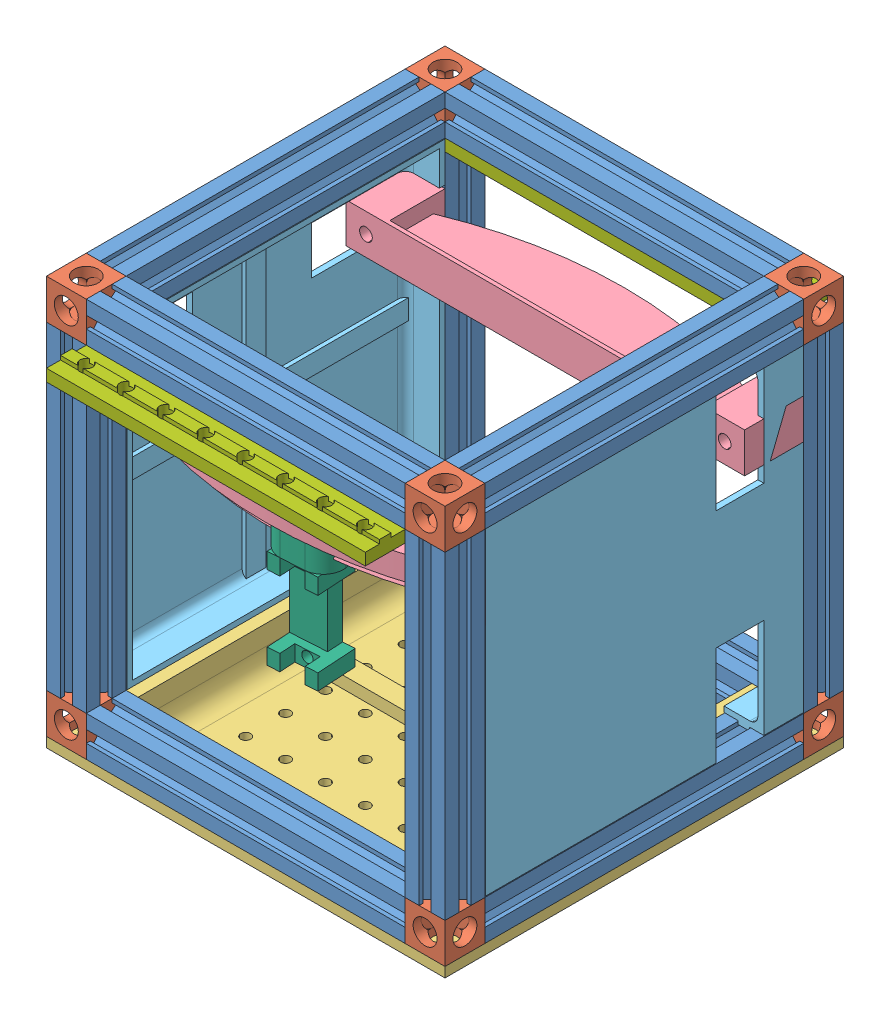
SolidWorks assembly SquareBeaconAssembly, configuration Default. Lengths in mm.
Overall size (100 102.5 120).
28 component instances, 7 part files, 90 mates.
Components (placement in the parent):
- Makerbeam50-1000mm-1: Makerbeam50-1000mm [80mm] at (14.161 43.4255 28.5525) size (10 10 80)
- MakerBeam-cube-1: MakerBeam-cube [Default] at (14.161 48.4255 113.5525) x (1 0 0) z (0 -1 0) size (10 10 10)
- Makerbeam50-1000mm-2: Makerbeam50-1000mm [80mm] at (14.161 128.4255 113.5525) x (1 0 0) z (0 -1 0) size (10 10 80)
- Makerbeam50-1000mm-3: Makerbeam50-1000mm [80mm] at (14.161 128.4255 23.5525) x (1 0 0) z (0 -1 0) size (10 10 80)
- Makerbeam50-1000mm-4: Makerbeam50-1000mm [80mm] at (-70.839 43.4255 113.5525) x (0 0 -1) z (1 0 0) size (10 10 80)
- Makerbeam50-1000mm-5: Makerbeam50-1000mm [80mm] at (-70.839 43.4255 23.5525) x (0 0 -1) z (1 0 0) size (10 10 80)
- MakerBeam-cube-3: MakerBeam-cube [Default] at (9.161 43.4255 23.5525) x (0 -1 0) z (1 0 0) size (10 10 10)
- MakerBeam-cube-4: MakerBeam-cube [Default] at (14.161 128.4255 23.5525) x (1 0 0) z (0 1 0) size (10 10 10)
- Makerbeam50-1000mm-6: Makerbeam50-1000mm [80mm] at (14.161 133.4255 28.5525) size (10 10 80)
- MakerBeam-cube-5: MakerBeam-cube [Default] at (14.161 133.4255 108.5525) size (10 10 10)
- Makerbeam50-1000mm-7: Makerbeam50-1000mm [80mm] at (9.161 133.4255 113.5525) x (0 0 1) z (-1 0 0) size (10 10 80)
- Makerbeam50-1000mm-8: Makerbeam50-1000mm [80mm] at (-70.839 133.4255 23.5525) x (0 0 -1) z (1 0 0) size (10 10 80)
- Makerbeam50-1000mm-9: Makerbeam50-1000mm [80mm] at (-75.839 133.4255 28.5525) size (10 10 80)
- Makerbeam50-1000mm-10: Makerbeam50-1000mm [80mm] at (-75.839 48.4255 113.5525) x (1 0 0) z (0 1 0) size (10 10 80)
- MakerBeam-cube-6: MakerBeam-cube [Default] at (-75.839 133.4255 28.5525) x (-1 0 0) z (0 0 -1) size (10 10 10)
- MakerBeam-cube-7: MakerBeam-cube [Default] at (-70.839 133.4255 113.5525) x (0 0 1) z (-1 0 0) size (10 10 10)
- MakerBeam-cube-8: MakerBeam-cube [Default] at (-70.839 43.4255 113.5525) x (0 -1 0) z (-1 0 0) size (10 10 10)
- Makerbeam50-1000mm-11: Makerbeam50-1000mm [80mm] at (-75.839 43.4255 28.5525) size (10 10 80)
- MakerBeam-cube-9: MakerBeam-cube [Default] at (-70.839 43.4255 23.5525) x (0 0 -1) z (-1 0 0) size (10 10 10)
- Makerbeam50-1000mm-12: Makerbeam50-1000mm [80mm] at (-75.839 128.4255 23.5525) x (1 0 0) z (0 -1 0) size (10 10 80)
- SquareBeaconSupportTop-1: SquareBeaconSupportTop [Default] at (-30.839 35.9255 68.5525) x (1 0 0) z (0 1 0) size (100 100 12.5)
- SquareBeaconVl530xSupport-1: SquareBeaconVl530xSupport [Default] at (-30.839 113.4255 8.5525) x (0 0 1) z (1 0 0) size (19.83 13 100)
- SquareBeaconSide-1: SquareBeaconSide [Default] at (-80.839 88.3255 68.4525) x (0 0 -1) z (1 0 0) size (81.5 81.5 10)
- SquareBeaconSide-2: SquareBeaconSide [Default] at (19.161 88.5255 68.4525) x (0 1 0) z (-1 0 0) size (81.5 81.5 10)
- SquareBeaconVl530xSupport-2: SquareBeaconVl530xSupport [Default] at (-30.839 113.4255 128.5525) x (0 0 -1) z (-1 0 0) size (19.83 13 100)
- TofSupport-1: TofSupport [Default] at (-33.9246 101.4255 -41.4401) x (0.998101 0 -0.061604) z (-0.061604 0 -0.998101) size (15.71 30.8 10.03)
- Bracket_ParallelCorner20x80_slotType2-1: Bracket_ParallelCorner20x80_slotType2 [Default] at (9.161 125.4255 23.5525) x (0 0 1) z (-1 0 0) size (20 4 80)
- Bracket_ParallelCorner20x80_slotType2-2: Bracket_ParallelCorner20x80_slotType2 [Default] at (-70.839 125.4255 113.5525) x (0 0 -1) z (1 0 0) size (20 4 80)
Mates (geometry in assembly coordinates):
- Coincident1: coincident anti-aligned: plane of Makerbeam50-1000mm-1 through (14.161 43.4255 108.5525) normal (0 0 1); plane of MakerBeam-cube-1 through (19.161 38.4255 108.5525) normal (0 0 -1)
- Coincident2: coincident aligned: plane of Makerbeam50-1000mm-1 through (19.161 48.4255 108.5525) normal (1 0 0); plane of MakerBeam-cube-1 through (19.161 38.4255 108.5525) normal (1 0 0)
- Coincident3: coincident aligned: plane of Makerbeam50-1000mm-1 through (9.161 48.4255 108.5525) normal (0 1 0); plane of MakerBeam-cube-1 through (14.161 48.4255 113.5525) normal (0 1 0)
- Coincident4: coincident anti-aligned: plane of MakerBeam-cube-1 through (14.161 48.4255 113.5525) normal (0 1 0); plane of Makerbeam50-1000mm-2 through (14.161 48.4255 113.5525) normal (0 -1 0)
- Coincident5: coincident aligned: plane of MakerBeam-cube-1 through (19.161 38.4255 108.5525) normal (1 0 0); plane of Makerbeam50-1000mm-2 through (19.161 48.4255 112.0525) normal (1 0 0)
- Coincident6: coincident aligned: plane of MakerBeam-cube-1 through (19.161 38.4255 118.5525) normal (0 0 1); plane of Makerbeam50-1000mm-2 through (15.661 48.4255 118.5525) normal (0 0 1)
- Coincident7: coincident: plane of Makerbeam50-1000mm-1 through (19.161 41.9255 108.5525) normal (1 0 0); plane of ? through (19.161 43.4255 23.5525) normal (1 0 0)
- Coincident8: coincident: plane of Makerbeam50-1000mm-1 through (15.661 48.4255 108.5525) normal (0 1 0); plane of ? through (19.161 48.4255 18.5525) normal (0 1 0)
- Coincident9: coincident anti-aligned: plane of Makerbeam50-1000mm-1 through (14.161 43.4255 28.5525) normal (0 0 -1); plane of ? through (19.161 38.4255 28.5525) normal (0 0 1)
- Coincident10: coincident: plane of ? through (19.161 48.4255 18.5525) normal (0 1 0); plane of Makerbeam50-1000mm-3 through (14.161 48.4255 23.4377) normal (0 -1 0)
- Coincident11: coincident: plane of ? through (19.161 48.4255 18.5525) normal (0 1 0); plane of Makerbeam50-1000mm-3 through (14.161 48.4255 23.4377) normal (0 -1 0)
- Coincident12: coincident aligned: plane of ? through (19.161 43.4255 23.5525) normal (1 0 0); plane of Makerbeam50-1000mm-3 through (19.161 48.4255 21.9377) normal (1 0 0)
- Coincident13: coincident anti-aligned: plane of MakerBeam-cube-1 through (9.161 38.4255 108.5525) normal (-1 0 0); plane of Makerbeam50-1000mm-4 through (9.161 43.4255 113.5525) normal (1 0 0)
- Coincident14: coincident aligned: plane of MakerBeam-cube-1 through (19.161 38.4255 118.5525) normal (0 0 1); plane of Makerbeam50-1000mm-4 through (9.161 38.4255 118.5525) normal (0 0 1)
- Coincident15: coincident aligned: plane of MakerBeam-cube-1 through (14.161 38.4255 113.5525) normal (0 -1 0); plane of Makerbeam50-1000mm-4 through (9.161 38.4255 115.0525) normal (0 -1 0)
- Coincident16: coincident anti-aligned: plane of ? through (9.161 43.4255 23.5525) normal (-1 0 0); plane of Makerbeam50-1000mm-5 through (9.161 112.5609 46.3386) normal (1 0 0)
- Coincident17: coincident anti-aligned: plane of Makerbeam50-1000mm-3 through (14.161 48.4255 23.5525) normal (0 -1 0); plane of MakerBeam-cube-3 through (19.161 48.4255 28.5525) normal (0 1 0)
- Coincident18: coincident aligned: plane of Makerbeam50-1000mm-3 through (9.161 48.4255 25.0525) normal (-1 0 0); plane of MakerBeam-cube-3 through (9.161 43.4255 23.5525) normal (-1 0 0)
- Coincident19: coincident anti-aligned: plane of Makerbeam50-1000mm-1 through (14.161 43.4255 28.5525) normal (0 0 -1); plane of MakerBeam-cube-3 through (19.161 38.4255 28.5525) normal (0 0 1)
- Coincident20: coincident anti-aligned: plane of Makerbeam50-1000mm-5 through (9.161 43.4255 23.5525) normal (1 0 0); plane of MakerBeam-cube-3 through (9.161 43.4255 23.5525) normal (-1 0 0)
- Coincident21: coincident aligned: plane of Makerbeam50-1000mm-1 through (9.161 44.9255 108.5525) normal (-1 0 0); plane of MakerBeam-cube-3 through (9.161 43.4255 23.5525) normal (-1 0 0)
- Coincident22: coincident aligned: plane of Makerbeam50-1000mm-5 through (9.161 38.4255 22.0525) normal (0 -1 0); plane of MakerBeam-cube-3 through (19.161 38.4255 28.5525) normal (0 -1 0)
- Coincident23: coincident aligned: plane of Makerbeam50-1000mm-5 through (9.161 41.9255 18.5525) normal (0 0 -1); plane of MakerBeam-cube-3 through (19.161 38.4255 18.5525) normal (0 0 -1)
- Coincident24: coincident aligned: plane of Makerbeam50-1000mm-3 through (12.661 48.4255 18.5525) normal (0 0 -1); plane of MakerBeam-cube-3 through (19.161 38.4255 18.5525) normal (0 0 -1)
- Coincident25: coincident anti-aligned: plane of Makerbeam50-1000mm-3 through (14.161 128.4255 23.5525) normal (0 1 0); plane of MakerBeam-cube-4 through (14.161 128.4255 23.5525) normal (0 -1 0)
- Coincident26: coincident aligned: plane of Makerbeam50-1000mm-3 through (15.661 48.4255 18.5525) normal (0 0 -1); plane of MakerBeam-cube-4 through (19.161 138.4255 18.5525) normal (0 0 -1)
- Coincident27: coincident aligned: plane of Makerbeam50-1000mm-3 through (9.161 48.4255 18.5525) normal (-1 0 0); plane of MakerBeam-cube-4 through (9.161 138.4255 28.5525) normal (-1 0 0)
- Coincident28: coincident aligned: plane of MakerBeam-cube-4 through (9.161 138.4255 28.5525) normal (-1 0 0); plane of Makerbeam50-1000mm-6 through (9.161 128.4255 108.5525) normal (-1 0 0)
- Coincident29: coincident aligned: plane of MakerBeam-cube-4 through (14.161 138.4255 23.5525) normal (0 1 0); plane of Makerbeam50-1000mm-6 through (15.661 138.4255 108.5525) normal (0 1 0)
- Coincident30: coincident anti-aligned: plane of MakerBeam-cube-4 through (19.161 138.4255 28.5525) normal (0 0 1); plane of Makerbeam50-1000mm-6 through (14.161 133.4255 28.5525) normal (0 0 -1)
- Coincident31: coincident aligned: plane of Makerbeam50-1000mm-1 through (15.661 38.4255 108.5525) normal (0 -1 0); plane of MakerBeam-cube-3 through (19.161 38.4255 28.5525) normal (0 -1 0)
- Coincident32: coincident aligned: plane of Makerbeam50-1000mm-2 through (9.161 48.4255 115.0525) normal (-1 0 0); plane of MakerBeam-cube-5 through (9.161 128.4255 118.5525) normal (-1 0 0)
- Coincident33: coincident aligned: plane of Makerbeam50-1000mm-6 through (15.661 138.4255 108.5525) normal (0 1 0); plane of MakerBeam-cube-5 through (19.161 138.4255 118.5525) normal (0 1 0)
- Coincident34: coincident anti-aligned: plane of Makerbeam50-1000mm-6 through (14.161 133.4255 108.5525) normal (0 0 1); plane of MakerBeam-cube-5 through (14.161 133.4255 108.5525) normal (0 0 -1)
- Coincident35: coincident anti-aligned: plane of MakerBeam-cube-5 through (9.161 128.4255 118.5525) normal (-1 0 0); plane of Makerbeam50-1000mm-7 through (9.161 133.4255 113.5525) normal (1 0 0)
- Coincident36: coincident aligned: plane of MakerBeam-cube-5 through (19.161 138.4255 118.5525) normal (0 1 0); plane of Makerbeam50-1000mm-7 through (-70.839 138.4255 115.0525) normal (0 1 0)
- Coincident37: coincident aligned: plane of MakerBeam-cube-5 through (14.161 133.4255 118.5525) normal (0 0 1); plane of Makerbeam50-1000mm-7 through (-70.839 131.9255 118.5525) normal (0 0 1)
- Coincident38: coincident anti-aligned: plane of MakerBeam-cube-4 through (9.161 138.4255 28.5525) normal (-1 0 0); plane of Makerbeam50-1000mm-8 through (9.161 133.4255 23.5525) normal (1 0 0)
- Coincident39: coincident aligned: plane of MakerBeam-cube-4 through (14.161 138.4255 23.5525) normal (0 1 0); plane of Makerbeam50-1000mm-8 through (9.161 138.4255 22.0525) normal (0 1 0)
- Coincident40: coincident aligned: plane of MakerBeam-cube-4 through (19.161 138.4255 18.5525) normal (0 0 -1); plane of Makerbeam50-1000mm-8 through (9.161 131.9255 18.5525) normal (0 0 -1)
- Coincident41: coincident aligned: plane of Makerbeam50-1000mm-8 through (9.161 138.4255 28.5525) normal (0 1 0); plane of Makerbeam50-1000mm-9 through (-74.339 138.4255 108.5525) normal (0 1 0)
- Coincident42: coincident aligned: plane of Makerbeam50-1000mm-8 through (9.161 131.9255 18.5525) normal (0 0 -1); plane of MakerBeam-cube-6 through (-75.839 133.4255 18.5525) normal (0 0 -1)
- Coincident43: coincident aligned: plane of Makerbeam50-1000mm-8 through (9.161 138.4255 22.0525) normal (0 1 0); plane of MakerBeam-cube-6 through (-80.839 138.4255 18.5525) normal (0 1 0)
- Coincident44: coincident anti-aligned: plane of Makerbeam50-1000mm-8 through (-70.839 133.4255 23.5525) normal (-1 0 0); plane of MakerBeam-cube-6 through (-70.839 128.4255 18.5525) normal (1 0 0)
- Coincident45: coincident aligned: plane of Makerbeam50-1000mm-9 through (-80.839 134.9255 108.5525) normal (-1 0 0); plane of MakerBeam-cube-6 through (-80.839 128.4255 18.5525) normal (-1 0 0)
- Coincident46: coincident anti-aligned: plane of Makerbeam50-1000mm-9 through (-75.839 133.4255 28.5525) normal (0 0 -1); plane of MakerBeam-cube-6 through (-75.839 133.4255 28.5525) normal (0 0 1)
- Coincident47: coincident anti-aligned: plane of Makerbeam50-1000mm-9 through (-75.839 133.4255 108.5525) normal (0 0 1); plane of MakerBeam-cube-7 through (-80.839 128.4255 108.5525) normal (0 0 -1)
- Coincident48: coincident aligned: plane of Makerbeam50-1000mm-7 through (-70.839 138.4255 115.0525) normal (0 1 0); plane of MakerBeam-cube-7 through (-80.839 138.4255 118.5525) normal (0 1 0)
- Coincident49: coincident anti-aligned: plane of Makerbeam50-1000mm-7 through (-70.839 133.4255 113.5525) normal (-1 0 0); plane of MakerBeam-cube-7 through (-70.839 133.4255 113.5525) normal (1 0 0)
- Coincident50: coincident aligned: plane of Makerbeam50-1000mm-10 through (-80.839 128.4255 112.0525) normal (-1 0 0); plane of MakerBeam-cube-7 through (-80.839 133.4255 113.5525) normal (-1 0 0)
- Coincident51: coincident anti-aligned: plane of Makerbeam50-1000mm-10 through (-75.839 128.4255 113.5525) normal (0 1 0); plane of MakerBeam-cube-7 through (-80.839 128.4255 118.5525) normal (0 -1 0)
- Coincident52: coincident aligned: plane of Makerbeam50-1000mm-10 through (-77.339 128.4255 118.5525) normal (0 0 1); plane of MakerBeam-cube-7 through (-80.839 128.4255 118.5525) normal (0 0 1)
- Coincident53: coincident anti-aligned: plane of Makerbeam50-1000mm-10 through (-75.839 48.4255 113.5525) normal (0 -1 0); plane of MakerBeam-cube-8 through (-80.839 48.4255 108.5525) normal (0 1 0)
- Coincident54: coincident aligned: plane of Makerbeam50-1000mm-10 through (-80.839 128.4255 118.5525) normal (-1 0 0); plane of MakerBeam-cube-8 through (-80.839 43.4255 113.5525) normal (-1 0 0)
- Coincident55: coincident aligned: plane of Makerbeam50-1000mm-4 through (9.161 44.9255 118.5525) normal (0 0 1); plane of MakerBeam-cube-8 through (-80.839 38.4255 118.5525) normal (0 0 1)
- Coincident56: coincident anti-aligned: plane of MakerBeam-cube-8 through (-80.839 38.4255 108.5525) normal (0 0 -1); plane of Makerbeam50-1000mm-11 through (-75.839 43.4255 108.5525) normal (0 0 1)
- Coincident57: coincident aligned: plane of MakerBeam-cube-8 through (-80.839 43.4255 113.5525) normal (-1 0 0); plane of Makerbeam50-1000mm-11 through (-80.839 38.4255 108.5525) normal (-1 0 0)
- Coincident58: coincident aligned: plane of MakerBeam-cube-8 through (-80.839 38.4255 108.5525) normal (0 -1 0); plane of Makerbeam50-1000mm-11 through (-74.339 38.4255 108.5525) normal (0 -1 0)
- Coincident59: coincident anti-aligned: plane of Makerbeam50-1000mm-11 through (-75.839 43.4255 28.5525) normal (0 0 -1); plane of MakerBeam-cube-9 through (-80.839 48.4255 28.5525) normal (0 0 1)
- Coincident60: coincident aligned: plane of Makerbeam50-1000mm-5 through (9.161 38.4255 25.0525) normal (0 -1 0); plane of MakerBeam-cube-9 through (-80.839 38.4255 18.5525) normal (0 -1 0)
- Coincident61: coincident aligned: plane of Makerbeam50-1000mm-11 through (-80.839 38.4255 108.5525) normal (-1 0 0); plane of MakerBeam-cube-9 through (-80.839 43.4255 23.5525) normal (-1 0 0)
- Coincident62: coincident anti-aligned: plane of MakerBeam-cube-6 through (-80.839 128.4255 18.5525) normal (0 -1 0); plane of Makerbeam50-1000mm-12 through (-75.839 128.4255 23.5525) normal (0 1 0)
- Coincident63: coincident aligned: plane of MakerBeam-cube-6 through (-80.839 128.4255 18.5525) normal (-1 0 0); plane of Makerbeam50-1000mm-12 through (-80.839 48.4255 18.5525) normal (-1 0 0)
- Coincident64: coincident aligned: plane of MakerBeam-cube-6 through (-75.839 133.4255 18.5525) normal (0 0 -1); plane of Makerbeam50-1000mm-12 through (-77.339 48.4255 18.5525) normal (0 0 -1)
- Coincident65: coincident anti-aligned: plane of Makerbeam50-1000mm-1 through (12.661 38.4255 108.5525) normal (0 -1 0); plane of SquareBeaconSupportTop-1 through (-80.839 38.4255 118.5525) normal (0 1 0)
- Coincident66: coincident aligned: plane of Makerbeam50-1000mm-11 through (-80.839 38.4255 108.5525) normal (-1 0 0); plane of SquareBeaconSupportTop-1 through (-80.839 48.4255 118.5525) normal (-1 0 0)
- Coincident67: coincident aligned: plane of Makerbeam50-1000mm-4 through (9.161 44.9255 118.5525) normal (0 0 1); plane of SquareBeaconSupportTop-1 through (-80.839 48.4255 118.5525) normal (0 0 1)
- Coincident68: coincident anti-aligned: plane of Makerbeam50-1000mm-10 through (-80.839 128.4255 108.5525) normal (0 0 -1); plane of SquareBeaconVl530xSupport-1 through (-80.839 117.4255 108.5525) normal (0 0 1)
- Coincident69: coincident aligned: plane of Makerbeam50-1000mm-10 through (-80.839 128.4255 112.0525) normal (-1 0 0); plane of SquareBeaconVl530xSupport-1 through (-80.839 117.4255 93.721) normal (-1 0 0)
- Distance1: distance = 15 mm anti-aligned: plane of SquareBeaconVl530xSupport-1 through (-70.9877 113.4255 94.6518) normal (0 1 0); plane of Makerbeam50-1000mm-7 through (-70.839 128.4255 112.0525) normal (0 -1 0)
- Coincident71: coincident anti-aligned: plane of Makerbeam50-1000mm-11 through (-80.839 48.4255 108.5525) normal (0 1 0); plane of SquareBeaconSide-1 through (-70.839 48.4255 108.3525) normal (0 -1 0)
- Coincident72: coincident aligned: plane of Makerbeam50-1000mm-11 through (-80.839 44.9255 108.5525) normal (-1 0 0); plane of SquareBeaconSide-1 through (-80.839 88.3255 68.4525) normal (-1 0 0)
- Coincident73: coincident anti-aligned: plane of Makerbeam50-1000mm-12 through (-80.839 48.4255 28.5525) normal (0 0 1); plane of SquareBeaconSide-1 through (-70.839 48.4255 28.5525) normal (0 0 -1)
- Coincident74: coincident anti-aligned: plane of Makerbeam50-1000mm-3 through (9.161 48.4255 28.5525) normal (0 0 1); plane of SquareBeaconSide-2 through (9.161 48.6255 28.5525) normal (0 0 -1)
- Coincident75: coincident aligned: plane of Makerbeam50-1000mm-6 through (19.161 138.4255 108.5525) normal (1 0 0); plane of SquareBeaconSide-2 through (19.161 88.5255 68.4525) normal (1 0 0)
- Coincident76: coincident anti-aligned: plane of Makerbeam50-1000mm-6 through (15.661 128.4255 108.5525) normal (0 -1 0); plane of SquareBeaconSide-2 through (9.161 128.4255 108.3525) normal (0 1 0)
- Coincident77: coincident anti-aligned: plane of Makerbeam50-1000mm-12 through (-80.839 48.4255 28.5525) normal (0 0 1); plane of SquareBeaconVl530xSupport-2 through (-77.289 117.4255 28.5525) normal (0 0 -1)
- Coincident78: coincident aligned: plane of Makerbeam50-1000mm-12 through (-80.839 48.4255 25.0525) normal (-1 0 0); plane of SquareBeaconVl530xSupport-2 through (-80.839 117.4255 28.5525) normal (-1 0 0)
- Coincident79: coincident aligned: plane of SquareBeaconVl530xSupport-1 through (-72.488 107.4255 97.8692) normal (0 -1 0); plane of SquareBeaconVl530xSupport-2 through (10.8101 107.4255 39.2359) normal (0 -1 0)
- Coincident80: coincident anti-aligned: plane of SquareBeaconVl530xSupport-1 through (-72.0442 104.4255 96.9175) normal (0 -1 0); plane of TofSupport-1 through (-16.5768 104.4255 110.0699) normal (0 1 0)
- Coincident81: coincident: circle of SquareBeaconVl530xSupport-1; point of TofSupport-1
- Coincident82: coincident: circle of SquareBeaconVl530xSupport-1; point of TofSupport-1
- Coincident83: coincident anti-aligned: plane of Makerbeam50-1000mm-9 through (-70.839 131.9255 108.5525) normal (1 0 0); plane of ? through (-70.839 114.4255 93.4923) normal (-1 0 0)
- Coincident84: coincident aligned: plane of Makerbeam50-1000mm-9 through (-74.339 138.4255 108.5525) normal (0 1 0); plane of ? through (-70.839 138.4255 93.4923) normal (0 1 0)
- Coincident85: coincident anti-aligned: plane of Makerbeam50-1000mm-8 through (9.161 128.4255 25.0525) normal (0 -1 0); plane of Bracket_ParallelCorner20x80_slotType2-1 through (-10.839 128.4255 25.0025) normal (0 1 0)
- Coincident86: coincident aligned: plane of Makerbeam50-1000mm-8 through (9.161 134.9255 28.5525) normal (0 0 1); plane of Bracket_ParallelCorner20x80_slotType2-1 through (-10.839 128.4255 28.5525) normal (0 0 1)
- Coincident87: coincident anti-aligned: plane of Makerbeam50-1000mm-12 through (-70.839 48.4255 22.0525) normal (1 0 0); plane of Bracket_ParallelCorner20x80_slotType2-1 through (-70.839 125.4255 23.5525) normal (-1 0 0)
- Coincident88: coincident anti-aligned: plane of Makerbeam50-1000mm-7 through (-70.839 128.4255 115.0525) normal (0 -1 0); plane of Bracket_ParallelCorner20x80_slotType2-2 through (-50.839 128.4255 118.5525) normal (0 1 0)
- Coincident89: coincident aligned: plane of Makerbeam50-1000mm-7 through (-70.839 134.9255 108.5525) normal (0 0 -1); plane of Bracket_ParallelCorner20x80_slotType2-2 through (-50.839 128.4255 108.5525) normal (0 0 -1)
- Coincident90: coincident anti-aligned: plane of Makerbeam50-1000mm-2 through (9.161 48.4255 115.0525) normal (-1 0 0); plane of Bracket_ParallelCorner20x80_slotType2-2 through (9.161 125.4255 113.5525) normal (1 0 0)
